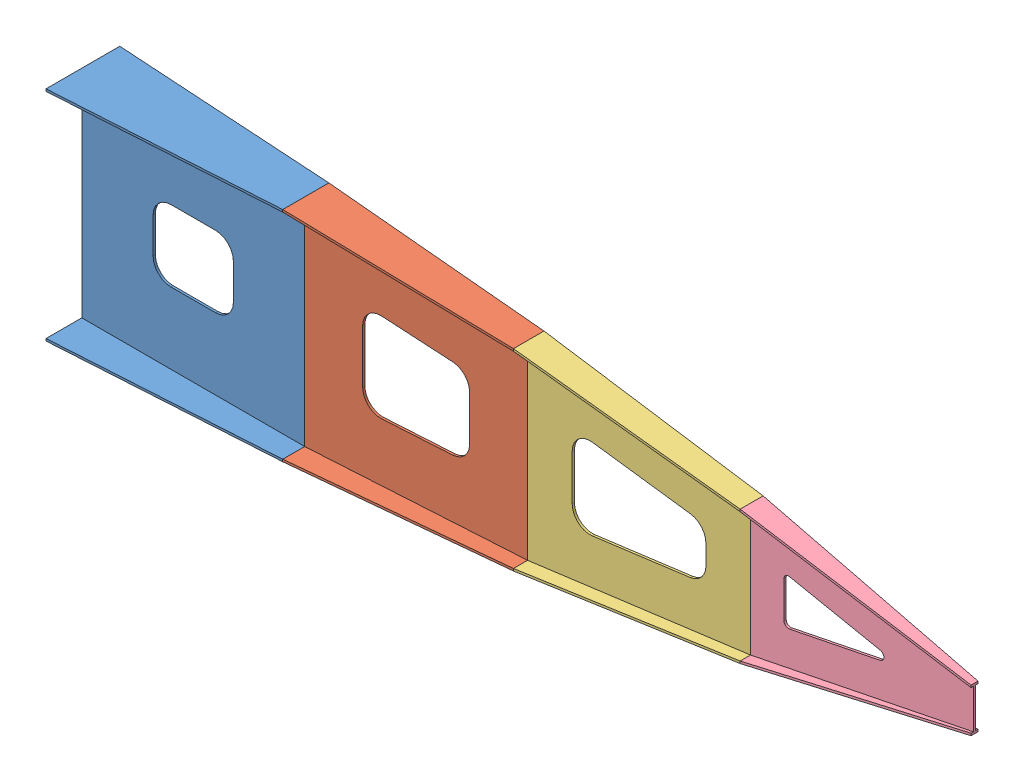
SolidWorks assembly 1.20 tolerance assembly, configuration Default. Lengths in mm.
Overall size (4000 980 331).
4 component instances, 4 part files, 9 mates.
Components (placement in the parent):
- 1-1: 1 [Default] at (-775.9263 612.0858 1043.8579) size (1000 980 331)
- 2-2: 2 [Default] at (224.0737 612.0858 1043.8579) size (1000 980 207)
- 3-2: 3 [Default] at (1224.0737 612.0858 1043.8579) size (1000 864 137)
- 4-2: 4 [Default] at (2224.0737 612.0858 1043.8579) size (1000 600 103)
Mates (geometry in assembly coordinates):
- Coincident39: coincident anti-aligned: plane of 1-1 through (224.0737 612.0858 1043.8579) normal (1 0 0); plane of 2-2 through (224.0737 612.0858 1043.8579) normal (-1 0 0)
- Coincident40: coincident anti-aligned: plane of 2-2 through (1224.0737 612.0858 1043.8579) normal (1 0 0); plane of 3-2 through (1224.0737 612.0858 1043.8579) normal (-1 0 0)
- Coincident42: coincident: point of 1-1; point of 2-2
- Coincident43: coincident: point of 1-1; point of 2-2
- Coincident44: coincident: point of 2-2; point of 3-2
- Coincident46: coincident: point of 2-2; point of 3-2
- Coincident49: coincident: point of 3-2; point of 4-2
- Coincident52: coincident aligned: plane of 3-2 through (1224.0737 612.0858 1053.8579) normal (0 0 1); plane of 4-2 through (2224.0737 612.0858 1053.8579) normal (0 0 1)
- Coincident53: coincident: point of 3-2; point of 4-2
